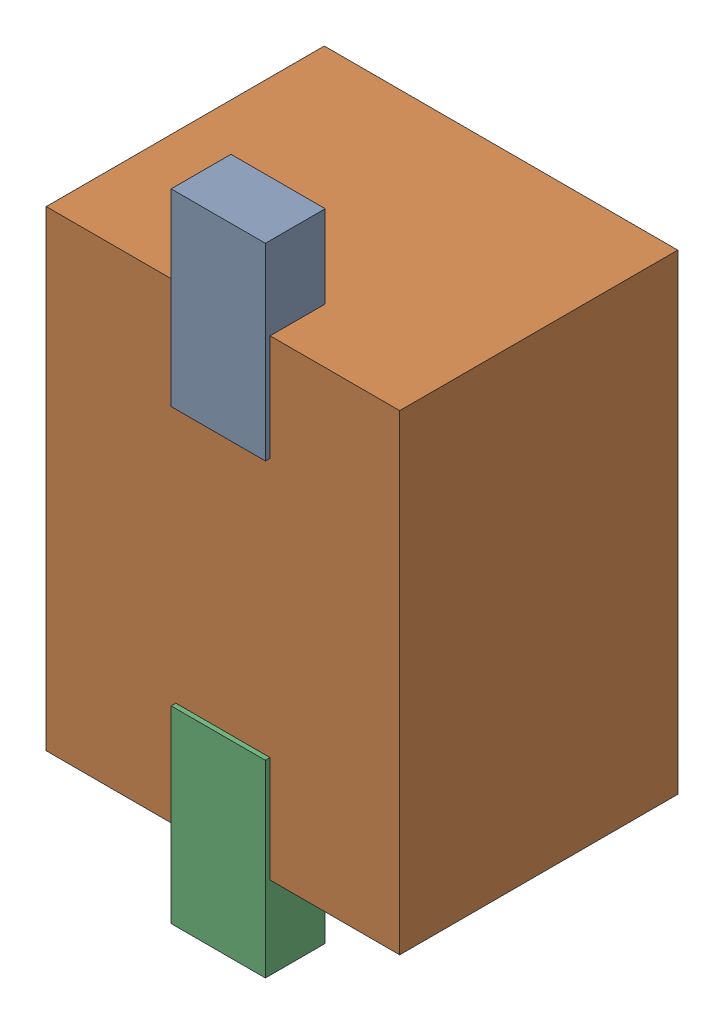
SolidWorks assembly D8, configuration Default. Lengths in mm.
Overall size (1.5 2.7 1.2).
6 component instances, 2 part files, 0 mates.
Components (placement in the parent):
- 710424336-1: 710424336 [Default] at (31.55 61.7 -0.6655) size (0.4 0.8 0.25)
  - Extruded (16)-1: Extruded (16) [Default] at origin size (0.4 0.8 0.25)
- 710424464-1: 710424464 [Default] at (31.55 60.75 -1.6115) size (1.5 2 1.18)
  - Extruded (17)-1: Extruded (17) [Default] at origin size (1.5 2 1.18)
- 710424336_1-1: 710424336_1 [Default] at (31.55 59.8 -0.6655) size (0.4 0.8 0.25)
  - Extruded (16)-1: Extruded (16) [Default] at origin size (0.4 0.8 0.25)
